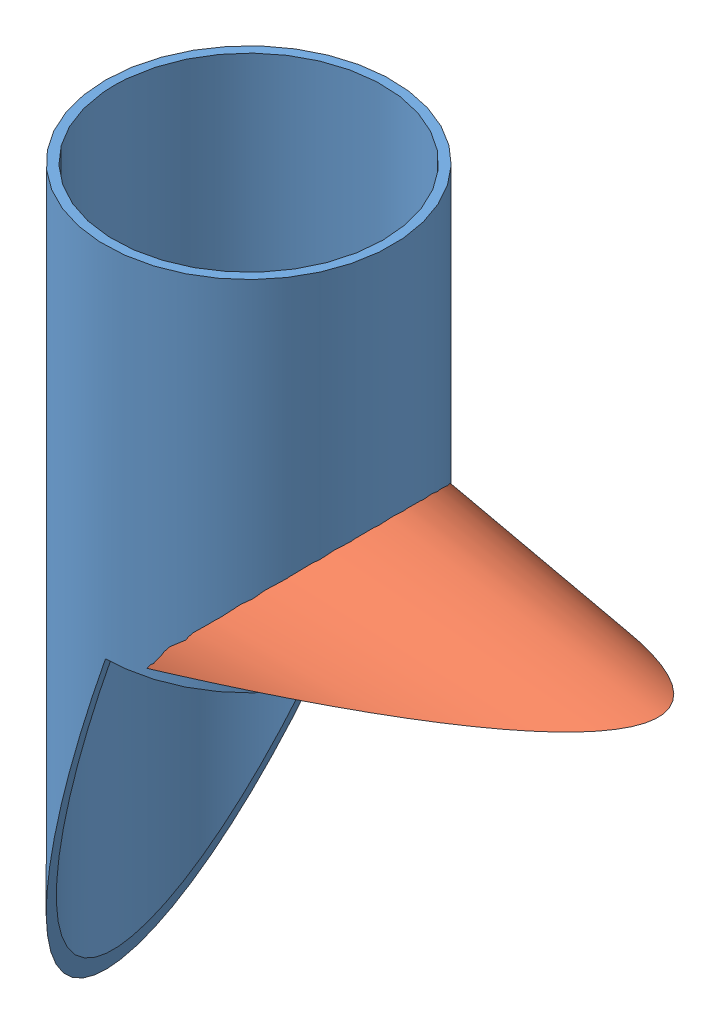
SolidWorks assembly Assem1, configuration Default. Lengths in mm.
Overall size (196.44 273.34 101.6).
2 component instances, 2 part files, 2 mates.
Components (placement in the parent):
- bottom_claw-1: bottom_claw [Default] at (52.7394 -630.1349 195.3032) size (101.6 273.34 101.6)
- top_claw-1: top_claw [Default] at (58.1281 -604.8624 195.3032) x (-0.017314 -0.99985 0) z (0 0 -1) size (50.8 144.78 101.6)
Mates (geometry in assembly coordinates):
- Coincident4: coincident: point of bottom_claw-1; point of top_claw-1
- Coincident5: coincident anti-aligned: line of bottom_claw-1 through (34.0017 -604.4447 144.5032) axis (0 0 1); line of top_claw-1 through (34.0017 -604.4447 147.0651) axis (0 0 -1)
